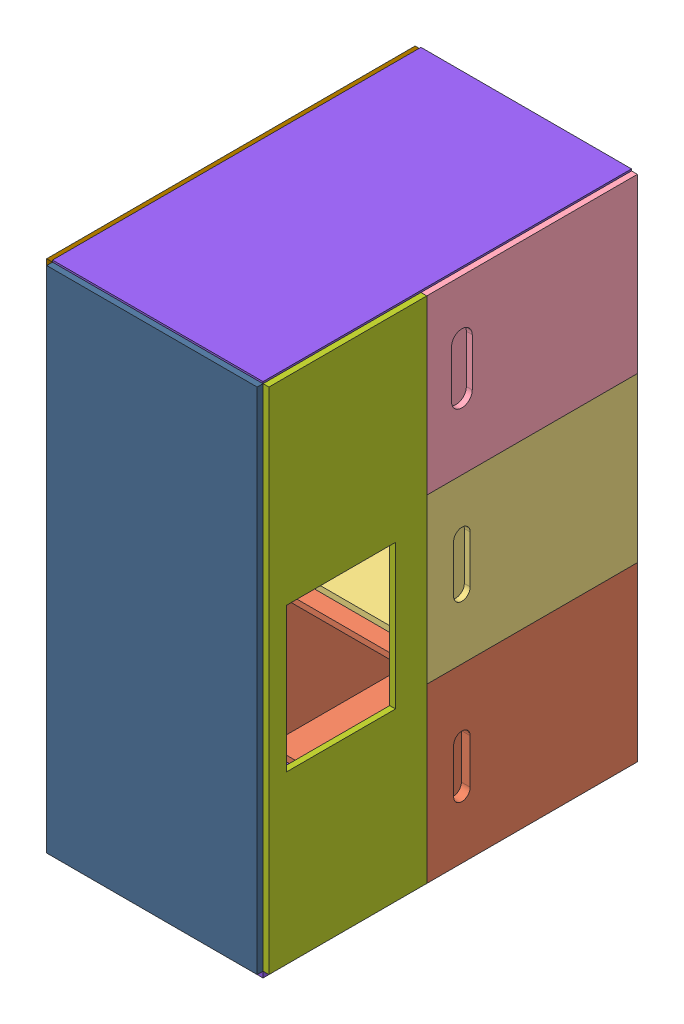
SolidWorks assembly 垃圾分类总装, configuration 默认. Lengths in mm.
Overall size (380 883.07 640).
15 component instances, 12 part files, 31 mates.
Components (placement in the parent):
- 框架-1: 框架 [默认<按加工>] at (-112.0395 3.4648 250) size (360 870 630)
- 垃圾桶-1: 垃圾桶 [默认] at (67.9605 -401.5352 -335) x (0 1 0) z (0 0 1) size (295 310 360)
- 垃圾桶1-1: 垃圾桶1 [默认] at (67.9605 -121.5352 -335) x (0 1 0) z (0 0 1) size (280 310 360)
- 垃圾桶2-1: 垃圾桶2 [默认] at (67.9605 158.4648 -335) x (0 1 0) z (0 0 1) size (295 310 360)
- 挡板模组-1: 挡板模组 [默认] at (-76.0461 258.0826 25) size (350 250 233.4) (flexible)
  - 挡板-1: 挡板 [默认] at (-30.9935 9.4905 -15) size (350 250 180)
  - 活动挡板-1: 活动挡板 [默认] at (-175.9935 102.8596 25.7354) x (0 0.749472 0.662036) z (1 0 0) size (105 30 290)
  - 活动挡板-2: 活动挡板 [默认] at (114.0065 -82.9629 26.0819) x (0 -0.719774 0.694208) z (-1 0 0) size (105 30 290)
- 零件3^垃圾分类总装-1: 零件3^垃圾分类总装 [默认] at (67.9605 3.4648 250) x (0 0 -1) z (1 0 0) size (270 870 10) (virtual)
- 零件4^垃圾分类总装-1: 零件4^垃圾分类总装 [默认] at (-112.0395 -431.5352 250) x (-1 0 0) z (0 -1 0) size (360 630 10) (virtual)
- 零件5^垃圾分类总装-1: 零件5^垃圾分类总装 [默认] at (-292.0395 3.4648 250) x (0 0 1) z (-1 0 0) size (630 870 10) (virtual)
- 零件4^垃圾分类总装-2: 零件4^垃圾分类总装 [默认] at (-112.0395 441.5352 250) x (-1 0 0) z (0 -1 0) size (360 630 10) (virtual)
- 零件6^垃圾分类总装-1: 零件6^垃圾分类总装 [默认] at (-112.0395 3.4648 265) size (360 870 10) (virtual)
- AI控制板-1: AI控制板 [默认] at (-117.0395 -26.5352 265) x (-1 0 0) z (0 0 -1) size (290 210 35)
- 瓶子-1: 瓶子 [默认] at (-176.6374 265.9502 6.8537) x (1 0 0) z (0 0.721459 0.692457) size (182 60 60)
Mates (geometry in assembly coordinates):
- 重合2: coincident: plane of 框架-1 through (62.7605 -401.5352 -350) normal (0 1 0); plane of 垃圾桶-1 through (67.9605 -401.5352 -35) normal (0 -1 0)
- 重合3: coincident: plane of 框架-1 through (67.9605 -406.7352 -350) normal (1 0 0); plane of 垃圾桶-1 through (67.9605 -401.5352 -335) normal (-1 0 0)
- 重合4: coincident: plane of 框架-1 through (43.1605 423.4648 -335) normal (0 0 1); plane of 垃圾桶-1 through (67.9605 -401.5352 -335) normal (0 0 -1)
- 重合5: coincident: plane of 框架-1 through (43.1605 423.4648 -335) normal (0 0 1); plane of 垃圾桶1-1 through (67.9605 -121.5352 -335) normal (0 0 -1)
- 重合6: coincident: plane of 框架-1 through (67.9605 423.4648 -14.8) normal (1 0 0); plane of 垃圾桶1-1 through (67.9605 -121.5352 -335) normal (-1 0 0)
- 重合7: coincident: plane of 垃圾桶-1 through (77.9605 -136.5352 -5) normal (0 1 0); plane of 垃圾桶1-1 through (77.9605 -136.5352 -5) normal (0 -1 0)
- 重合8: coincident: plane of 框架-1 through (43.1605 423.4648 -335) normal (0 0 1); plane of 垃圾桶2-1 through (67.9605 158.4648 -335) normal (0 0 -1)
- 重合9: coincident: plane of 框架-1 through (67.9605 433.2648 -350) normal (1 0 0); plane of 垃圾桶2-1 through (67.9605 158.4648 -335) normal (-1 0 0)
- 重合10: coincident: plane of 垃圾桶1-1 through (77.9605 143.4648 -5) normal (0 1 0); plane of 垃圾桶2-1 through (77.9605 143.4648 -5) normal (0 -1 0)
- 重合13: coincident: plane of 框架-1 through (43.1605 423.4648 10) normal (0 0 1); plane of 挡板模组-1/挡板-1 through (-107.0395 267.5731 10) normal (0 0 -1)
- 重合14: coincident: plane of 框架-1 through (67.9605 423.4648 -14.8) normal (1 0 0); plane of 挡板模组-1/挡板-1 through (67.9605 142.5731 40) normal (1 0 0)
- 在位1: in place: plane of 框架-1 through (67.9605 -406.7352 -310) normal (1 0 0); plane of ? through (67.9605 0 0) normal (1 0 0); moOrthogonalPlaneRef_w of 框架-1 through (67.9605 -406.7352 -310) normal (1 0 0); plane of ? through (67.9605 0 0) normal (0 1 0); plane of 框架-1 through (67.9605 -406.7352 -310) normal (1 0 0); plane of ? through (67.9605 0 0) normal (0 0 -1); plane of 框架-1 through (67.9605 -406.7352 -350) normal (1 0 0); unknown of 零件3^垃圾分类总装-1
- 重合15: coincident: plane of 框架-1; plane of 零件3^垃圾分类总装-1
- 重合16: coincident: moOrthogonalPlaneRef_w of 框架-1 through (67.9605 3.4648 250) normal (0 1 0); plane of 零件3^垃圾分类总装-1 through (67.9605 3.4648 250) normal (0 1 0)
- 重合17: coincident: moOrthogonalPlaneRef_w of 框架-1 through (67.9605 3.4648 250) normal (0 0 1); plane of 零件3^垃圾分类总装-1 through (67.9605 3.4648 250) normal (0 0 -1)
- 在位2: in place: plane of 框架-1 through (-267.2395 -431.5352 250) normal (0 -1 0); plane of ? through (0 -431.5352 0) normal (0 -1 0); plane of 框架-1 through (-267.2395 -431.5352 250) normal (0 -1 0); plane of ? through (0 -431.5352 0) normal (0 0 -1); plane of 框架-1 through (-267.2395 -431.5352 250) normal (0 -1 0); plane of ? through (0 -431.5352 0) normal (-1 0 0); plane of 框架-1 through (-267.2395 -431.5352 250) normal (0 -1 0); unknown of 零件4^垃圾分类总装-1
- 重合18: coincident: plane of 框架-1; plane of 零件4^垃圾分类总装-1
- 重合19: coincident: moOrthogonalPlaneRef_w of 框架-1 through (-112.0395 -431.5352 250) normal (0 0 -1); plane of 零件4^垃圾分类总装-1 through (-112.0395 -431.5352 250) normal (0 0 -1)
- 重合20: coincident: moOrthogonalPlaneRef_w of 框架-1 through (-112.0395 -431.5352 250) normal (1 0 0); plane of 零件4^垃圾分类总装-1 through (-112.0395 -431.5352 250) normal (-1 0 0)
- 在位3: in place: plane of 框架-1 through (-292.0395 423.4648 259.8) normal (-1 0 0); plane of ? through (-292.0395 0 0) normal (-1 0 0); plane of 框架-1 through (-292.0395 423.4648 259.8) normal (-1 0 0); plane of ? through (-292.0395 0 0) normal (0 1 0); plane of 框架-1 through (-292.0395 423.4648 259.8) normal (-1 0 0); plane of ? through (-292.0395 0 0) normal (0 0 1); plane of 框架-1 through (-292.0395 423.4648 259.8) normal (-1 0 0); unknown of 零件5^垃圾分类总装-1
- 重合21: coincident: plane of 框架-1; plane of 零件5^垃圾分类总装-1
- 重合22: coincident: moOrthogonalPlaneRef_w of 框架-1 through (-292.0395 3.4648 250) normal (0 1 0); plane of 零件5^垃圾分类总装-1 through (-292.0395 3.4648 250) normal (0 1 0)
- 重合23: coincident: moOrthogonalPlaneRef_w of 框架-1 through (-292.0395 3.4648 250) normal (0 0 -1); plane of 零件5^垃圾分类总装-1 through (-292.0395 3.4648 250) normal (0 0 1)
- 在位4: in place: plane of 框架-1 through (-286.8395 423.4648 265) normal (0 0 1); plane of ? through (0 0 265) normal (0 0 1); plane of 框架-1 through (-286.8395 423.4648 265) normal (0 0 1); plane of ? through (0 0 265) normal (0 1 0); plane of 框架-1 through (-286.8395 423.4648 265) normal (0 0 1); plane of ? through (0 0 265) normal (1 0 0); plane of 框架-1 through (-286.8395 423.4648 265) normal (0 0 1); unknown of 零件6^垃圾分类总装-1
- 重合24: coincident: plane of 框架-1; plane of 零件6^垃圾分类总装-1
- 重合25: coincident: moOrthogonalPlaneRef_w of 框架-1 through (-112.0395 3.4648 265) normal (0 1 0); plane of 零件6^垃圾分类总装-1 through (-112.0395 3.4648 265) normal (0 1 0)
- 重合26: coincident: moOrthogonalPlaneRef_w of 框架-1 through (-112.0395 3.4648 265) normal (-1 0 0); plane of 零件6^垃圾分类总装-1 through (-112.0395 3.4648 265) normal (1 0 0)
- 重合27: coincident: plane of 零件6^垃圾分类总装-1 through (-112.0395 3.4648 265) normal (0 0 -1); plane of AI控制板-1 through (-117.0395 -26.5352 265) normal (0 0 1)
- 重合28: coincident: plane of 框架-1 through (-262.0395 423.4648 240.2) normal (1 0 0); plane of AI控制板-1 through (-262.0395 -131.5352 235) normal (-1 0 0)
- 距离1: distance = 270 mm: plane of AI控制板-1 through (27.9605 -131.5352 235) normal (0 -1 0); plane of 框架-1 through (52.9605 -401.5352 259.8) normal (0 1 0)
- 相切2: tangent: cylinder of 瓶子-1 through (-176.6374 265.9502 6.8537) axis (-1 0 0) radius 30; plane of 挡板模组-1/活动挡板-1 through (37.9605 360.9422 50.7354) normal (0 -0.662036 0.749472)
